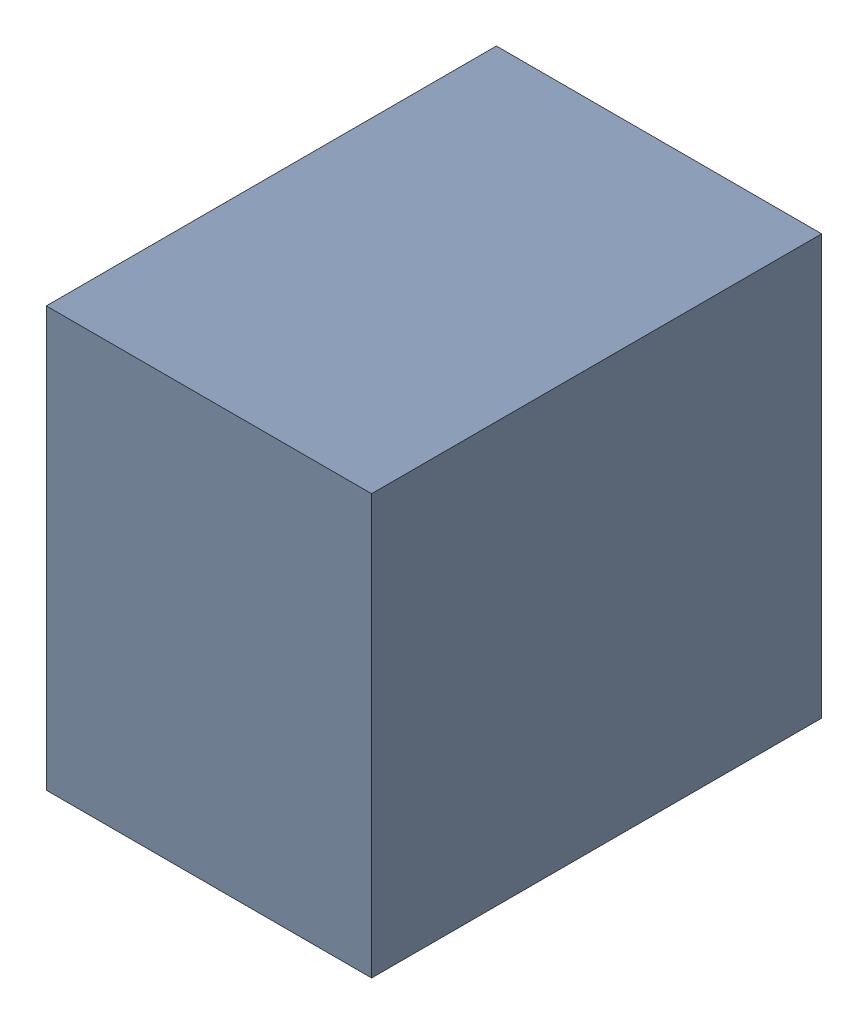
SolidWorks assembly R317_2PCB, configuration Default. Lengths in mm.
Overall size (3.18 4.1 4.4).
2 component instances, 1 part files, 0 mates.
Components (placement in the parent):
- 846485736-1: 846485736 [Default] at (123.6999 97.6 0) size (3.18 4.1 4.4)
  - Extruded_41-1: Extruded_41 [Default] at origin size (3.18 4.1 4.4)
